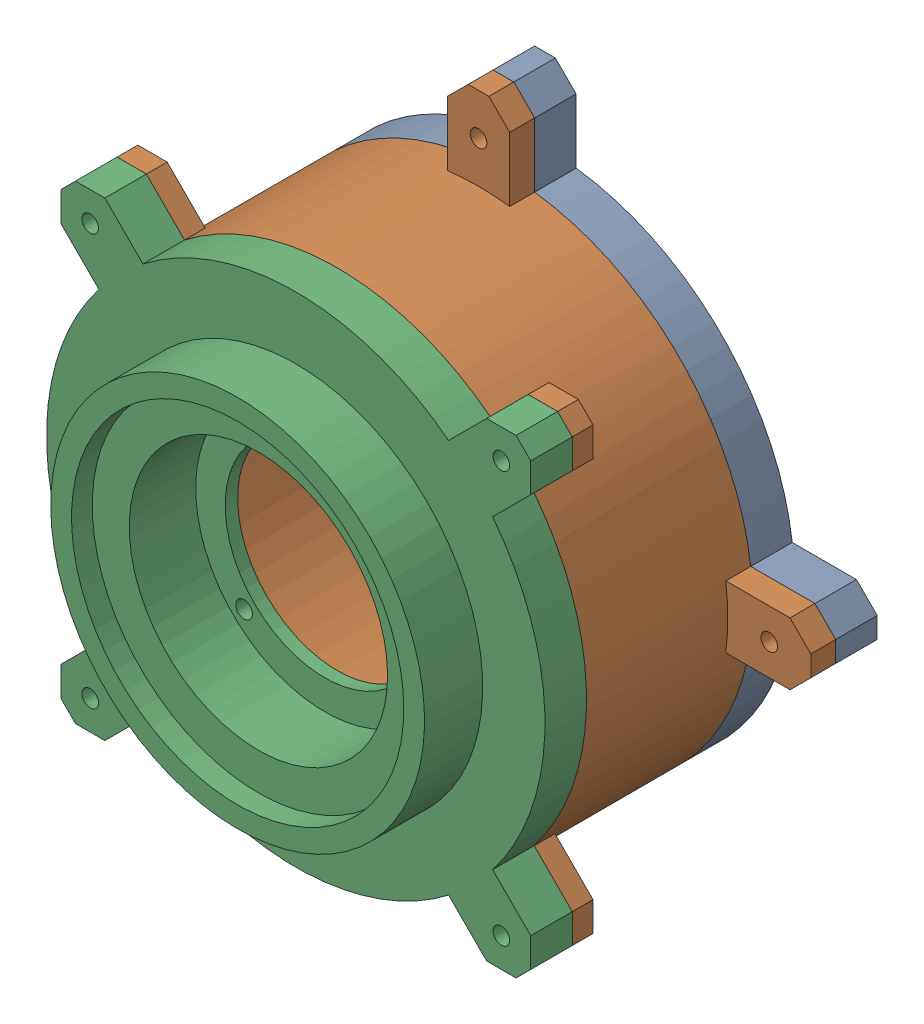
SolidWorks assembly HeleBasis, configuration Default. Lengths in mm.
Overall size (219.2 219.2 74).
3 component instances, 3 part files, 5 mates.
Components (placement in the parent):
- Basis-1: Basis [Default] at (25.997 92.1001 47.0469) size (160 160 10)
- BasisPart2-2: BasisPart2 [Default] at (25.997 92.1001 57.0469) size (160 160 40)
- BasisPart3-1: BasisPart3 [Default] at (25.997 92.1001 97.0469) x (0.707107 0.707107 0) z (0 0 1) size (155 155 24)
Mates (geometry in assembly coordinates):
- Coincident4: coincident anti-aligned: plane of Basis-1 through (25.997 92.1001 57.0469) normal (0 0 1); plane of BasisPart2-2 through (25.997 92.1001 57.0469) normal (0 0 -1)
- Coincident7: coincident: point of Basis-1; point of BasisPart2-2
- Coincident14: coincident anti-aligned: plane of BasisPart2-2 through (25.997 92.1001 97.0469) normal (0 0 1); plane of BasisPart3-1 through (25.997 92.1001 97.0469) normal (0 0 -1)
- Coincident15: coincident: point of BasisPart2-2; point of BasisPart3-1
- Coincident18: coincident: point of BasisPart2-2; point of BasisPart3-1
